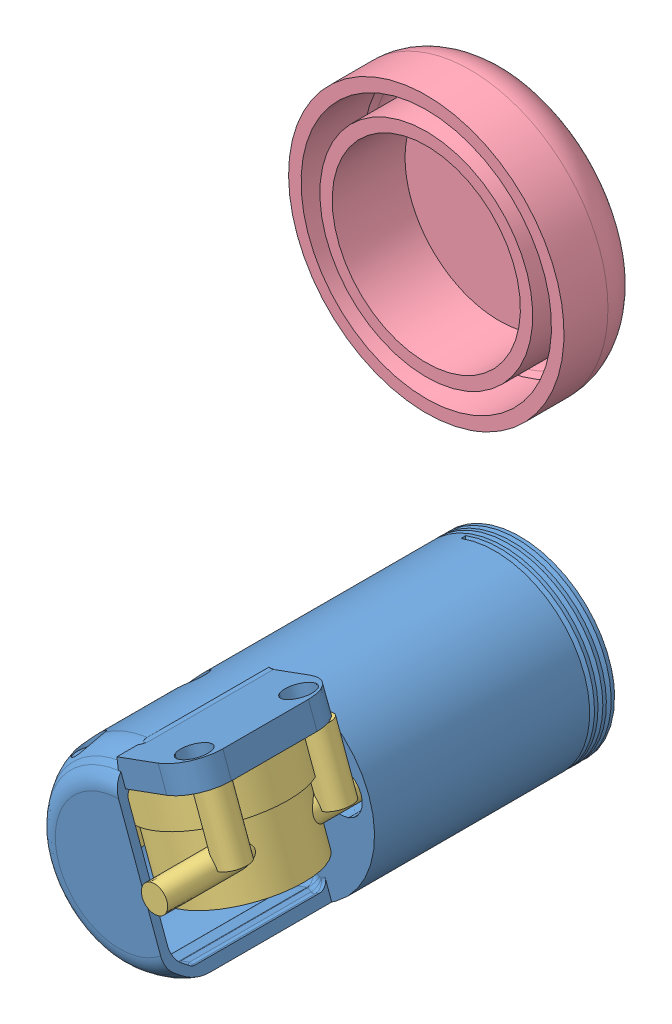
SolidWorks assembly Prototype_1, configuration Default. Lengths in mm.
Overall size (283.78 283.91 744.18).
5 component instances, 5 part files, 10 mates.
Components (placement in the parent):
- Electronics Housing-1: Electronics Housing [Default] at (21.2242 7.4689 0) x (-0.939253 -0.343227 0) z (0 0 1) size (47.32 45.79 96.95)
- Electronics Housing - Copy-2: Electronics Housing - Copy [Default] at (21.2476 7.4775 55) x (0.939253 0.343227 0) z (0 0 -1) size (3.81 289.94 744.18)
- Flowmeter Mockup-1: Flowmeter Mockup [Default] at (20.8352 23.8293 74.1679) x (0 0 -1) z (-0.939253 -0.343227 0) size (56.25 24.5 34.5)
- HF_Cap-1: HF_Cap [Default] at (-124.9873 -46.7596 -123.5988) x (-0.924412 -0.381396 0) z (0.381396 -0.924412 0) size (66 20 66)
- 9V-1: 9V [Default] at (13.3847 4.6042 55) x (-0.343227 0.939253 0) z (-0.939253 -0.343227 0) size (26 48.8 16)
Mates (geometry in assembly coordinates):
- Coincident3: coincident anti-aligned: plane of Electronics Housing-1 through (16.1441 26.8461 90) normal (0.343227 -0.939253 0); plane of Electronics Housing - Copy-2 through (12.6608 25.5732 0) normal (-0.343227 0.939253 0)
- Coincident4: coincident anti-aligned: plane of Electronics Housing-1 through (29.5838 -9.5805 55) normal (0 0 -1); plane of Electronics Housing - Copy-2 through (26.3272 -11.147 55) normal (0 0 1)
- Concentric2: concentric anti-aligned: cylinder of Electronics Housing-1 through (16.1681 26.102 90) axis (0 0 -1) radius 0.25; cylinder of Electronics Housing - Copy-2 through (16.1681 26.102 0) axis (0 0 1) radius 0.25
- Coincident6: coincident anti-aligned: plane of Electronics Housing-1 through (21.2242 7.4689 0) normal (0 0 -1); plane of assembly through (0 0 0) normal (0 0 1)
- Concentric4: concentric aligned: circle of Electronics Housing-1; circle of Flowmeter Mockup-1
- Coincident7: coincident: point of Electronics Housing-1
- Coincident10: coincident anti-aligned: plane of Electronics Housing-1 through (29.5838 -9.5805 55) normal (0 0 -1); plane of 9V-1 through (14.9467 16.3541 55) normal (0 0 1)
- Coincident11: coincident anti-aligned: plane of Electronics Housing - Copy-2 through (20.8988 7.35 55) normal (-0.939253 -0.343227 0); plane of 9V-1 through (24.5026 -2.5121 10.3) normal (0.939253 0.343227 0)
- Distance1: distance = 0.25 mm anti-aligned: plane of 9V-1 through (23.0126 -5.7183 10.3) normal (0.343227 -0.939253 0); plane of Electronics Housing - Copy-2 through (25.4465 -5.0951 0) normal (-0.343227 0.939253 0)
- Parallel3: parallel anti-aligned: plane of Electronics Housing-1 through (30.4169 27.4723 86) normal (0.343227 -0.939253 0); plane of Flowmeter Mockup-1 through (20.8352 23.8293 74.1679) normal (-0.343227 0.939253 0)
